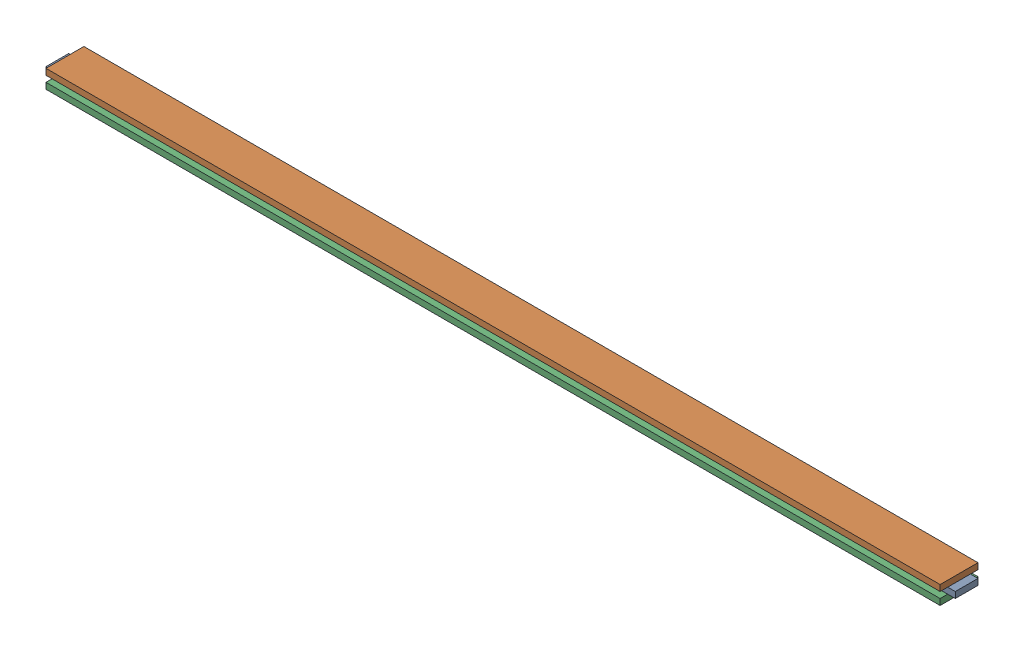
SolidWorks assembly БокЛ, configuration По умолчанию. Lengths in mm.
Overall size (1200 24 50).
3 component instances, 2 part files, 6 mates.
Components (placement in the parent):
- планкаСР_Л-1: планкаСР_Л [По умолчанию] at origin size (1200 8 30)
- планкаК_Л-1: планкаК_Л [По умолчанию] at (0 8 0) size (1180 8 50)
- планкаК_Л-2: планкаК_Л [По умолчанию] at (0 -8 0) size (1180 8 50)
Mates (geometry in assembly coordinates):
- Совпадение2: coincident aligned: plane of планкаК_Л-1; plane of планкаК_Л-2
- Совпадение3: coincident aligned: plane of планкаК_Л-1; plane of планкаК_Л-2
- Совпадение4: coincident anti-aligned: plane of планкаСР_Л-1 through (0 8 0) normal (0 1 0); plane of планкаК_Л-1 through (-20 8 0) normal (0 -1 0)
- Расстояние1: distance = 10 mm aligned: plane of планкаСР_Л-1 through (-600 8 15) normal (0 0 1); plane of планкаК_Л-1 through (-590 16 25) normal (0 0 1)
- Совпадение6: coincident anti-aligned: plane of планкаСР_Л-1 through (0 0 0) normal (0 -1 0); plane of планкаК_Л-2 through (-20 0 0) normal (0 1 0)
- Расстояние2: distance = 10 mm aligned: plane of планкаСР_Л-1 through (-600 8 -15) normal (-1 0 0); plane of планкаК_Л-1 through (-590 16 -25) normal (-1 0 0)
